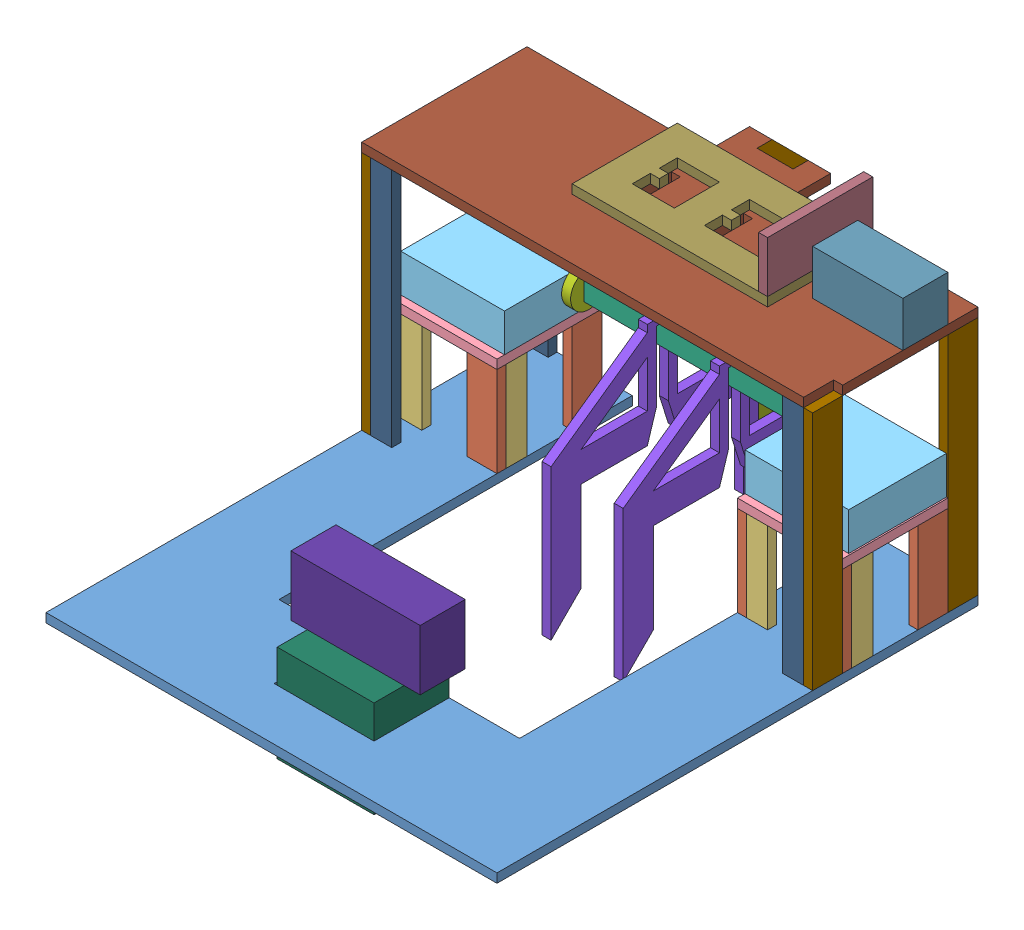
SolidWorks assembly Robot, configuration Default. Lengths in mm.
Overall size (150 132 184).
60 component instances, 20 part files, 54 mates.
Components (placement in the parent):
- Base plate-1: Base plate [Default] at (-32.2297 -11.3342 23.6884) size (150 3 160)
- MotorStage-1: MotorStage [Default] at (-135.047 -12.3322 16.4198) x (0 0 1) z (1 0 0) size (35 33 35)
  - Leg-1: Leg [Default] at (-10.5952 -8.2697 7.7093) size (10 30 10)
    - Leg_Part1-1: Leg_Part1 [Default] at (-27.1362 -25.7283 21.608) size (10 30 3)
    - Leg_Part2-1: Leg_Part2 [Default] at (0.3707 -25.7283 0) size (3 30 7)
  - platform-1: platform [Default] at (-50.2314 -36.998 45.3173) size (35 3 35)
  - Leg-2: Leg [Default] at (-87.8394 -8.2697 5.6811) x (0 0 -1) z (1 0 0) size (10 30 10)
    - Leg_Part1-1: Leg_Part1 [Default] at (-27.1362 -25.7283 21.608) size (10 30 3)
    - Leg_Part2-1: Leg_Part2 [Default] at (0.3707 -25.7283 0) size (3 30 7)
  - Leg-3: Leg [Default] at (-89.8676 -8.2697 82.9253) x (-1 0 0) z (0 0 -1) size (10 30 10)
    - Leg_Part1-1: Leg_Part1 [Default] at (-27.1362 -25.7283 21.608) size (10 30 3)
    - Leg_Part2-1: Leg_Part2 [Default] at (0.3707 -25.7283 0) size (3 30 7)
  - Leg-4: Leg [Default] at (-12.6234 -8.2697 84.9535) x (0 0 1) z (-1 0 0) size (10 30 10)
    - Leg_Part1-1: Leg_Part1 [Default] at (-27.1362 -25.7283 21.608) size (10 30 3)
    - Leg_Part2-1: Leg_Part2 [Default] at (0.3707 -25.7283 0) size (3 30 7)
- MotorStage-2: MotorStage [Default] at (-20.047 -12.3322 16.4198) x (0 0 1) z (1 0 0) size (35 33 35)
  - Leg-1: Leg [Default] at (-10.5952 -8.2697 7.7093) size (10 30 10)
    - Leg_Part1-1: Leg_Part1 [Default] at (-27.1362 -25.7283 21.608) size (10 30 3)
    - Leg_Part2-1: Leg_Part2 [Default] at (0.3707 -25.7283 0) size (3 30 7)
  - platform-1: platform [Default] at (-50.2314 -36.998 45.3173) size (35 3 35)
  - Leg-2: Leg [Default] at (-87.8394 -8.2697 5.6811) x (0 0 -1) z (1 0 0) size (10 30 10)
    - Leg_Part1-1: Leg_Part1 [Default] at (-27.1362 -25.7283 21.608) size (10 30 3)
    - Leg_Part2-1: Leg_Part2 [Default] at (0.3707 -25.7283 0) size (3 30 7)
  - Leg-3: Leg [Default] at (-89.8676 -8.2697 82.9253) x (-1 0 0) z (0 0 -1) size (10 30 10)
    - Leg_Part1-1: Leg_Part1 [Default] at (-27.1362 -25.7283 21.608) size (10 30 3)
    - Leg_Part2-1: Leg_Part2 [Default] at (0.3707 -25.7283 0) size (3 30 7)
  - Leg-4: Leg [Default] at (-12.6234 -8.2697 84.9535) x (0 0 1) z (-1 0 0) size (10 30 10)
    - Leg_Part1-1: Leg_Part1 [Default] at (-27.1362 -25.7283 21.608) size (10 30 3)
    - Leg_Part2-1: Leg_Part2 [Default] at (0.3707 -25.7283 0) size (3 30 7)
- Motor-1: Motor [Default] at (25.0203 24.6658 -35.0616) size (34.5 12.6 32.5)
- Motor-2: Motor [Default] at (-89.4797 37.2658 -35.0616) x (1 0 0) z (0 0 -1) size (34.5 12.6 32.5)
- Picking mechanism-1: Picking mechanism [Default] at (22.1989 39.8179 -77.3919) size (80 76 74)
  - Rod-1: Rod [Default] at (-54.4286 -7.1522 32.0803) size (80 6 3)
  - Ends-1: Ends [Default] at (-94.4286 0 0) size (3 12 12)
  - Ends-2: Ends [Default] at (-14.4286 0 67.1607) x (-1 0 0) z (0 0 -1) size (3 12 12)
  - Arm-1: Arm [Default] at (-45.4286 -64.1538 34.081) size (3 75 74)
  - Arm-2: Arm [Default] at (-69.4286 -64.1538 34.081) size (3 75 74)
- arm_holder_leg-1: arm_holder_leg [Default] at (15.8818 55.3573 -14.0101) size (10 80 10)
  - arm_holder_leg1-1: arm_holder_leg1 [Default] at (25.3885 -63.6916 2.6985) size (3 80 10)
  - arm_holder_leg2-1: arm_holder_leg2 [Default] at (0 -63.6916 0) size (10 80 10)
- arm_holder_leg-2: arm_holder_leg [Default] at (15.8818 7.9742 -53.613) x (1 0 0) z (0 0 -1) size (10 80 10)
  - arm_holder_leg1-1: arm_holder_leg1 [Default] at (25.3885 -63.6916 2.6985) size (3 80 10)
  - arm_holder_leg2-1: arm_holder_leg2 [Default] at (0 -63.6916 0) size (10 80 10)
- arm_holder_leg-3: arm_holder_leg [Default] at (-80.3412 55.3573 -53.613) x (-1 0 0) z (0 0 -1) size (10 80 10)
  - arm_holder_leg1-1: arm_holder_leg1 [Default] at (25.3885 -63.6916 2.6985) size (3 80 10)
  - arm_holder_leg2-1: arm_holder_leg2 [Default] at (0 -63.6916 0) size (10 80 10)
- arm_holder_leg-4: arm_holder_leg [Default] at (-80.3412 7.9742 -14.0101) x (-1 0 0) z (0 0 1) size (10 80 10)
  - arm_holder_leg1-1: arm_holder_leg1 [Default] at (25.3885 -63.6916 2.6985) size (3 80 10)
  - arm_holder_leg2-1: arm_holder_leg2 [Default] at (0 -63.6916 0) size (10 80 10)
- arm_holder_platform-1: arm_holder_platform [Default] at (0 71.6658 0) size (150 3 74)
- arm_lock-1: arm_lock [Default] at (0 74.6658 -4) size (65 3 35)
- arm_lock_push_face-1: arm_lock_push_face [Default] at (0 77.6658 -4) x (1 0 0) z (0 1 0) size (3 35 17)
- Push-Pull solenoid-1: Push-Pull solenoid [Default] at (27.7703 74.6658 -43.8116) size (30 15 15)
- Color Sensor-1: Color Sensor [Default] at (-31.7297 -13.4342 81.1884) x (1 0 0) z (0 1 0) size (32.2 25 32.2)
- tcs3200-1: tcs3200 [Default] at (-33.7297 -11.5359 -85.3109) x (1 0 0) z (0 -1 0) size (28.4 10 28.4)
- ultrasonic sensor-1: ultrasonic sensor [Default] at (-31.7797 12.6658 56.1884) x (1 0 0) z (0 -1 0) size (43 15 20)
- IR sensor holder-1: IR sensor holder [Default] at (0 59.6658 0) size (12 72 5)
- TCRT5000-1: TCRT5000 [Default] at (-32.8297 9.7641 -72.4116) x (-1 0 0) z (0 0 1) size (10.2 10 5.8)
- box guides-1: box guides [Default] at (-3 -36.3342 0) size (3 25 10)
- box guides-2: box guides [Default] at (-45.2 -36.3342 0) size (3 25 10)
Mates (geometry in assembly coordinates):
- Coincident3: coincident aligned: line of Base plate-1 through (-107.2297 -8.3342 -61.3116) axis (0 0 1); line of MotorStage-1/Leg-2/Leg_Part2-1 through (-107.2297 -8.3342 -48.3116) axis (0 0 1)
- Distance4: distance = 10 mm: line of MotorStage-1/Leg-2/Leg_Part1-1 through (-107.2297 -8.3342 -51.3116) axis (1 0 0); line of Base plate-1 through (-107.2297 -8.3342 -61.3116) axis (1 0 0)
- Distance5: distance = 10 mm: line of MotorStage-2/Leg-2/Leg_Part1-1 through (7.7703 -8.3342 -51.3116) axis (1 0 0); line of Base plate-1 through (7.7703 -8.3342 -61.3116) axis (1 0 0)
- Coincident7: coincident anti-aligned: line of Base plate-1 through (7.7703 -8.3342 56.1884) axis (0 0 -1); line of MotorStage-2/Leg-2/Leg_Part2-1 through (7.7703 -8.3342 -48.3116) axis (0 0 1)
- Coincident8: coincident anti-aligned: line of MotorStage-2/platform-1 through (7.7703 24.6658 -16.3116) axis (0 0 -1); line of Motor-1 through (7.7703 24.6658 -51.3116) axis (0 0 1)
- Coincident9: coincident anti-aligned: line of MotorStage-2/platform-1 through (7.7703 24.6658 -51.3116) axis (1 0 0); line of Motor-1 through (42.2703 24.6658 -51.3116) axis (-1 0 0)
- Coincident12: coincident aligned: line of MotorStage-1/platform-1 through (-107.2297 24.6658 -51.3116) axis (1 0 0); line of Motor-2 through (-106.7297 24.6658 -51.3116) axis (1 0 0)
- Coincident13: coincident aligned: line of MotorStage-1/platform-1 through (-72.2297 24.6658 -51.3116) axis (0 0 1); line of Motor-2 through (-72.2297 24.6658 -51.3116) axis (0 0 1)
- Coincident14: coincident anti-aligned: plane of Motor-1 through (7.7703 37.2658 -51.3116) normal (-1 0 0); plane of Picking mechanism-1/Ends-2 through (7.7703 39.8179 -10.2313) normal (1 0 0)
- Distance1: distance = 5 mm: line of Picking mechanism-1/Rod-1 through (7.7703 29.6658 -42.3116) axis (0 0 -1); line of Motor-1 through (7.7703 24.6658 -51.3116) axis (0 0 1)
- Distance3: distance = 6 mm: line of Picking mechanism-1/Rod-1 through (7.7703 29.6658 -45.3116) axis (0 1 0); line of Motor-1 through (7.7703 37.2658 -51.3116) axis (0 -1 0)
- Parallel1: parallel aligned: plane of Base plate-1 through (-32.2297 -11.3342 -61.3116) normal (0 0 -1); plane of MotorStage-1/Leg-3/Leg_Part2-1 through (-52.1217 -8.3342 -51.3116) normal (0 0 -1)
- Parallel2: parallel aligned: plane of Base plate-1 through (-107.2297 -8.3342 -51.3116) normal (-1 0 0); plane of MotorStage-1/Leg-1/Leg_Part1-1 through (-107.2297 -8.3342 -26.3116) normal (-1 0 0)
- Parallel3: parallel aligned: plane of Base plate-1 through (42.7703 -8.3342 -51.3116) normal (1 0 0); plane of MotorStage-2/Leg-3/Leg_Part1-1 through (42.7703 -8.3342 -41.3116) normal (1 0 0)
- Coincident26: coincident aligned: line of Base plate-1 through (42.7703 -8.3342 98.6884) axis (0 0 -1); line of arm_holder_leg-1/arm_holder_leg1-1 through (42.7703 -8.3342 -6.3116) axis (0 0 -1)
- Coincident27: coincident aligned: line of MotorStage-2/Leg-4/Leg_Part1-1 through (42.7703 -8.3342 -16.3116) axis (-1 0 0); line of arm_holder_leg-1/arm_holder_leg1-1 through (42.7703 -8.3342 -16.3116) axis (-1 0 0)
- Coincident30: coincident anti-aligned: line of Base plate-1 through (7.7703 -8.3342 -61.3116) axis (1 0 0); line of arm_holder_leg-2/arm_holder_leg2-1 through (39.7703 -8.3342 -61.3116) axis (-1 0 0)
- Coincident31: coincident anti-aligned: line of Base plate-1 through (42.7703 -8.3342 98.6884) axis (0 0 -1); line of arm_holder_leg-2/arm_holder_leg1-1 through (42.7703 -8.3342 -61.3116) axis (0 0 1)
- Coincident36: coincident aligned: line of Base plate-1 through (-107.2297 -8.3342 -61.3116) axis (0 0 1); line of arm_holder_leg-3/arm_holder_leg1-1 through (-107.2297 -8.3342 -61.3116) axis (0 0 1)
- Coincident37: coincident aligned: line of Base plate-1 through (-107.2297 -8.3342 -61.3116) axis (1 0 0); line of arm_holder_leg-3/arm_holder_leg2-1 through (-104.2297 -8.3342 -61.3116) axis (1 0 0)
- Coincident38: coincident anti-aligned: line of Base plate-1 through (-107.2297 -8.3342 -61.3116) axis (0 0 1); line of arm_holder_leg-4/arm_holder_leg1-1 through (-107.2297 -8.3342 -6.3116) axis (0 0 -1)
- Coincident39: coincident anti-aligned: line of MotorStage-1/Leg-1/Leg_Part1-1 through (-104.2297 -8.3342 -16.3116) axis (-1 0 0); line of arm_holder_leg-4/arm_holder_leg1-1 through (-107.2297 -8.3342 -16.3116) axis (1 0 0)
- Coincident40: coincident aligned: line of arm_holder_leg-3/arm_holder_leg2-1 through (-104.2297 71.6658 -61.3116) axis (1 0 0); line of arm_holder_platform-1 through (-107.2297 71.6658 -61.3116) axis (1 0 0)
- Coincident41: coincident aligned: line of arm_holder_leg-3/arm_holder_leg1-1 through (-107.2297 71.6658 -61.3116) axis (0 0 1); line of arm_holder_platform-1 through (-107.2297 71.6658 -61.3116) axis (0 0 1)
- Coincident42: coincident anti-aligned: plane of arm_holder_platform-1 through (0 74.6658 0) normal (0 1 0); plane of arm_lock-1 through (0 74.6658 -4) normal (0 -1 0)
- Distance6: distance = 4 mm: line of arm_holder_platform-1 through (-20.2297 74.6658 -49.3116) axis (-1 0 0); line of arm_lock-1 through (-20.2297 74.6658 -45.3116) axis (-1 0 0)
- Coincident44: coincident aligned: line of arm_holder_platform-1 through (-20.2297 74.6658 -38.3116) axis (0 0 -1); line of arm_lock-1 through (-20.2297 74.6658 -42.3116) axis (0 0 -1)
- InPlace1: in place: plane of arm_lock-1 through (0 77.6658 -4) normal (0 1 0); plane of ? through (0 77.6658 0) normal (0 1 0); moOrthogonalPlaneRef_w of arm_lock-1 through (0 77.6658 -4) normal (0 1 0); plane of ? through (0 77.6658 0) normal (0 0 -1); plane of arm_lock-1 through (0 77.6658 -4) normal (0 1 0); line of ? through (-55 0 77.6658) axis (0 1 0); plane of arm_lock-1 through (0 77.6658 -4) normal (0 1 0); unknown of arm_lock_push_face-1
- Coincident45: coincident aligned: plane of arm_lock-1; plane of arm_lock_push_face-1
- Coincident46: coincident aligned: moOrthogonalPlaneRef_w of arm_lock-1 through (0 77.6658 -4) normal (0 0 -1); plane of arm_lock_push_face-1 through (0 77.6658 -4) normal (0 0 -1)
- Coincident47: coincident anti-aligned: moOrthogonalPlaneRef_w of arm_lock-1 through (0 77.6658 -4) normal (-1 0 0); plane of arm_lock_push_face-1
- Distance10: distance = 10 mm aligned: plane of arm_lock_push_face-1 through (0 94.6658 -26.3116) normal (0 0 1); plane of Push-Pull solenoid-1 through (12.7703 89.6658 -36.3116) normal (0 0 1)
- Coincident54: coincident anti-aligned: plane of arm_holder_platform-1 through (0 74.6658 0) normal (0 1 0); plane of Push-Pull solenoid-1 through (27.7703 74.6658 -43.8116) normal (0 -1 0)
- Distance11: distance = 5 mm anti-aligned: plane of arm_lock_push_face-1 through (7.7703 94.6658 -4) normal (1 0 0); plane of Push-Pull solenoid-1 through (12.7703 89.6658 -51.3116) normal (-1 0 0)
- Coincident56: coincident anti-aligned: plane of Base plate-1 through (-15.6297 -11.3342 81.1884) normal (0 0 -1); plane of Color Sensor-1 through (-31.7297 -13.4342 81.1884) normal (0 0 1)
- Coincident57: coincident anti-aligned: plane of Base plate-1 through (-15.6297 -11.3342 56.1884) normal (-1 0 0); plane of Color Sensor-1 through (-15.6297 -29.5342 56.1884) normal (1 0 0)
- Distance12: distance = 11 mm: line of Base plate-1 through (-48.8297 -8.3342 81.1884) axis (1 0 0); line of Color Sensor-1 through (-47.8297 2.6658 81.1884) axis (1 0 0)
- Coincident59: coincident anti-aligned: line of Picking mechanism-1/Arm-1 through (-23.2297 2.6641 -75.3109) axis (1 0 0); line of tcs3200-1 through (-19.5297 2.6641 -75.3109) axis (-1 0 0)
- Coincident60: coincident anti-aligned: plane of Picking mechanism-1/Arm-1 through (-23.2297 2.6641 -75.3109) normal (0 0 -1); plane of tcs3200-1 through (-33.7297 -11.5359 -75.3109) normal (0 0 1)
- Distance13: distance = 0.7 mm: line of Picking mechanism-1/Arm-2 through (-47.2297 2.6641 -75.3109) axis (0 -1 0); line of tcs3200-1 through (-47.9297 2.6641 -75.3109) axis (0 -1 0)
- Coincident64: coincident anti-aligned: plane of Color Sensor-1 through (-47.8297 2.6658 56.1884) normal (0 1 0); plane of ultrasonic sensor-1 through (-53.2797 2.6658 71.1884) normal (0 -1 0)
- Coincident65: coincident aligned: line of Color Sensor-1 through (-47.8297 2.6658 56.1884) axis (1 0 0); line of ultrasonic sensor-1 through (-53.2797 2.6658 56.1884) axis (1 0 0)
- Distance14: distance = 5.35 mm: line of ultrasonic sensor-1 through (-10.2797 2.6658 71.1884) axis (0 0 -1); line of Color Sensor-1 through (-15.6297 2.6658 56.1884) axis (0 0 1)
- Coincident67: coincident aligned: line of arm_holder_platform-1 through (-39.7297 74.6658 -70.3116) axis (1 0 0); line of IR sensor holder-1 through (-39.7297 74.6658 -70.3116) axis (1 0 0)
- Coincident68: coincident aligned: line of arm_holder_platform-1 through (-27.7297 74.6658 -70.3116) axis (0 0 -1); line of IR sensor holder-1 through (-27.7297 74.6658 -70.3116) axis (0 0 -1)
- Parallel5: parallel anti-aligned: plane of IR sensor holder-1 through (0 9.7641 0) normal (0 -1 0); plane of TCRT5000-1 through (-32.8297 9.7641 -72.4116) normal (0 1 0)
- Coincident70: coincident anti-aligned: line of IR sensor holder-1 through (-39.7297 9.7641 -75.3116) axis (1 0 0); line of TCRT5000-1 through (-27.7297 9.7641 -75.3116) axis (-1 0 0)
- Coincident71: coincident aligned: line of IR sensor holder-1 through (-27.7297 9.7641 -75.3116) axis (0 0 1); line of TCRT5000-1 through (-27.7297 9.7641 -75.3116) axis (0 0 1)
- Coincident73: coincident anti-aligned: plane of Base plate-1 through (-32.2297 -11.3342 23.6884) normal (0 -1 0); plane of box guides-1 through (-3 -11.3342 0) normal (0 1 0)
- Distance16: distance = 3 mm: line of Base plate-1 through (-15.6297 -11.3342 81.1884) axis (0 0 -1); line of box guides-1 through (-12.6297 -11.3342 56.1884) axis (0 0 1)
- Coincident75: coincident aligned: line of Base plate-1 through (7.7703 -11.3342 56.1884) axis (-1 0 0); line of box guides-1 through (-9.6297 -11.3342 56.1884) axis (-1 0 0)
- Coincident76: coincident: plane of Base plate-1 through (-32.2297 -11.3342 23.6884) normal (0 -1 0); plane of box guides-2 through (-53.2673 -11.3342 0) normal (0 1 0)
- Coincident77: coincident: line of Base plate-1 through (-48.8297 -11.3342 56.1884) axis (-1 0 0); line of box guides-2 through (-59.897 -11.3342 56.1884) axis (-1 0 0)
- Distance18: distance = 3 mm: line of box guides-2 through (-51.8297 -11.3342 56.1884) axis (0 0 1); line of Base plate-1 through (-48.8297 -11.3342 56.1884) axis (0 0 1)
